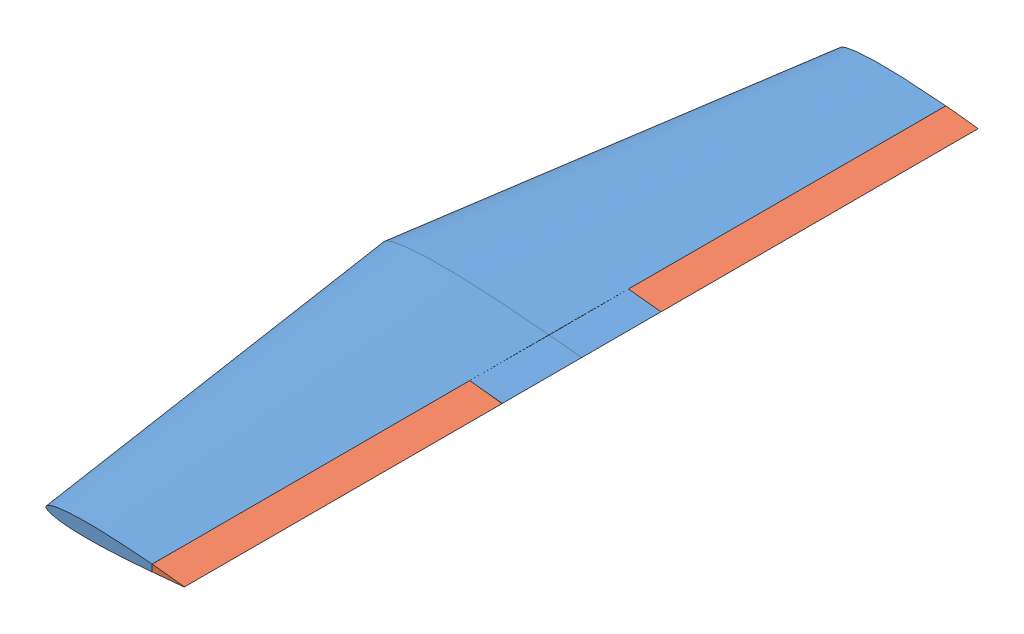
SolidWorks assembly Horizontal tail, configuration Default. Lengths in mm.
Overall size (85.11 18.32 338.26).
2 component instances, 2 part files, 2 mates.
Components (placement in the parent):
- Horizontal tail-1: Horizontal tail [Default] at (-66.2781 -20.6872 26.8582) size (85.11 18.32 338.25)
- Elevator-2: Elevator [Default] at (-66.35 -20.0514 26.8582) x (0.999962 -0.008739 0) z (0 0 1) size (14.77 3.27 338.26)
Mates (geometry in assembly coordinates):
- Concentric2: concentric anti-aligned: cylinder of Horizontal tail-1 through (6.4062 -20.6872 -59.3418) axis (0 0 1) radius 0.4; cylinder of Elevator-2 through (6.4062 -20.6872 115.6582) axis (0 0 -1) radius 0.4
- Coincident1: coincident anti-aligned: plane of Horizontal tail-1 through (4.4062 -10.6872 -6.9418) normal (0 0 -1); plane of Elevator-2 through (10.5673 684.3033 -6.9418) normal (0 0 1)
